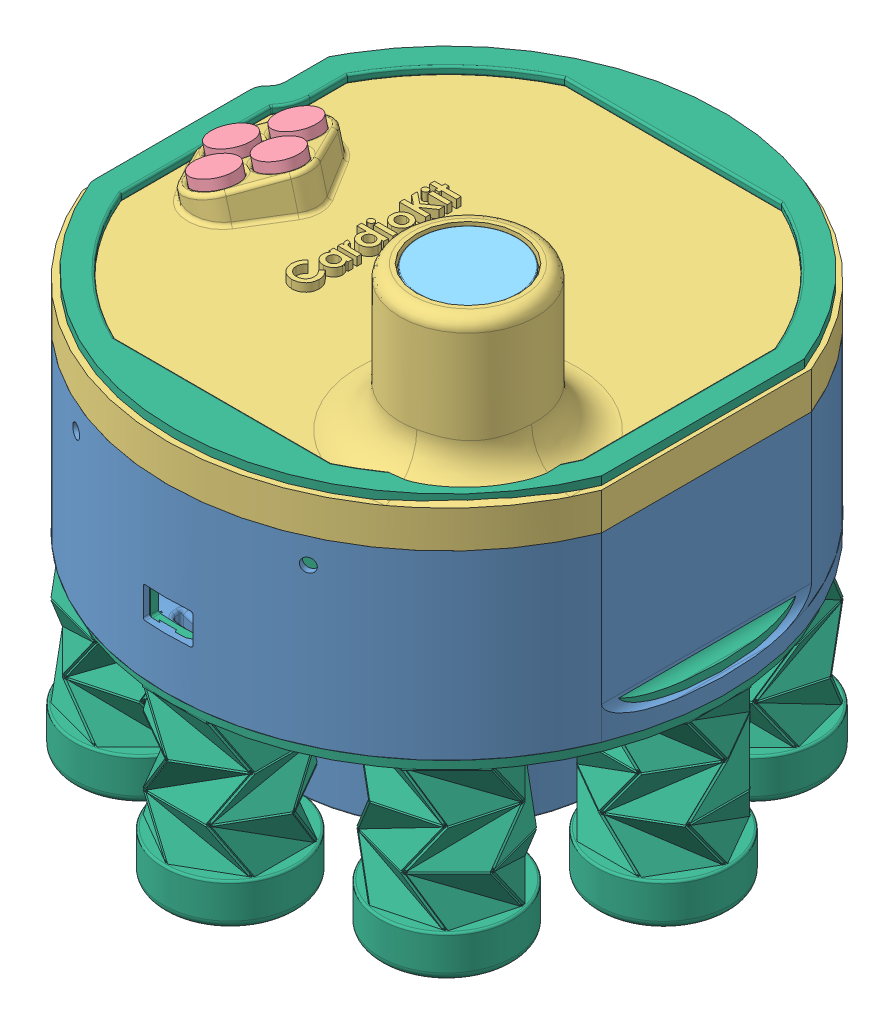
SolidWorks assembly CardioKit-Full-Assembly-R20, configuration Default. Lengths in mm.
Overall size (68.7 67.73 68.7).
46 component instances, 13 part files, 29 mates.
Components (placement in the parent):
- CardioKit_Shell_R00-1: CardioKit_Shell_R00 [Default] at (3.2379 48.1061 53.8338) size (67.95 39.64 67.99)
- CardioKitPCB_R01-1: CardioKitPCB_R01 [Default] at (3.2379 59.6836 53.8338) x (1 0 0) z (0 1 0) size (60.71 65.8 14.79)
- CardioKit_Shell_Top_R30-1: CardioKit_Shell_Top_R30 [Default] at (3.2379 72.6061 53.8338) x (1 0 0.000154) z (-0.000154 0 1) size (63 33.5 67.95)
- LED_5mm-1: LED_5mm [Default] at (-17.6564 71.4439 59.4672) x (-0.010288 -0.002809 -0.999943) z (0.965871 0.258804 -0.010664) size (5 11.8 5)
- LED_5mm-2: LED_5mm [Default] at (-14.7811 72.2141 54.4677) x (0.000332 0.000037 -1) z (0.965926 0.258819 0.00033) size (5 11.8 5)
- LED_5mm-3: LED_5mm [Default] at (-20.5766 70.6612 54.4666) x (0.005602 0.001449 -0.999983) z (0.96591 0.258815 0.005786) size (5 11.8 5)
- LED_5mm-4: LED_5mm [Default] at (-17.6544 71.4439 49.4672) x (0.014169 0.003744 -0.999893) z (0.965822 0.258792 0.014655) size (5 11.8 5)
- Sintered12mmElectrode-1: Sintered12mmElectrode [Default] at (20.3171 91.8561 68.3635) x (-0.837169 0 -0.546944) z (-0.546944 0 0.837169) size (12 5.38 12)
- Sintered12mmElectrode-2: Sintered12mmElectrode [Default] at (-29.0123 60.1061 53.8338) x (0 -0.932668 0.360735) z (0 0.360735 0.932668) size (12 5.38 12)
- CardioKit_Sock_R30-1: CardioKit_Sock_R30 [Default] at (3.2553 48.1061 53.8013) x (1 0 0.000196) z (-0.000196 0 1) size (68.69 51.15 68.69)
- ElectrodeAssembly-1: ElectrodeAssembly [Default] at (-23.7364 22.823 43.8978) size (11 27.01 11)
  - SpikedElectrodes-1: SpikedElectrodes [Default] at (0.6918 2.1948 9.9135) size (10.25 6.45 10.25)
  - ElectrodeHolder-1: ElectrodeHolder [Default] at (0.6918 4.8948 9.9135) x (0.999995 0 -0.003075) z (0.003075 0 0.999995) size (10 0.6 10)
  - Spring_R20_1pt7mmFinal2_Narrower-2: Spring_R20_1pt7mmFinal2_Narrower [Default] at (0.6918 3.1948 9.9135) x (1 0 0) z (0 -1 0) size (11 11 1.7)
- ElectrodeAssembly-2: ElectrodeAssembly [Default] at (-8.81 22.823 27.7342) x (0.707107 0 0.707107) z (-0.707107 0 0.707107) size (11 27.01 11)
  - SpikedElectrodes-1: SpikedElectrodes [Default] at (0.6918 2.1948 9.9135) size (10.25 6.45 10.25)
  - ElectrodeHolder-1: ElectrodeHolder [Default] at (0.6918 4.8948 9.9135) x (0.999995 0 -0.003075) z (0.003075 0 0.999995) size (10 0.6 10)
  - Spring_R20_1pt7mmFinal2_Narrower-2: Spring_R20_1pt7mmFinal2_Narrower [Default] at (0.6918 3.1948 9.9135) x (1 0 0) z (0 -1 0) size (11 11 1.7)
- ElectrodeAssembly-3: ElectrodeAssembly [Default] at (13.1739 22.823 26.8595) x (0 0 1) z (-1 0 0) size (11 27.01 11)
  - SpikedElectrodes-1: SpikedElectrodes [Default] at (0.6918 2.1948 9.9135) size (10.25 6.45 10.25)
  - ElectrodeHolder-1: ElectrodeHolder [Default] at (0.6918 4.8948 9.9135) x (0.999995 0 -0.003075) z (0.003075 0 0.999995) size (10 0.6 10)
  - Spring_R20_1pt7mmFinal2_Narrower-2: Spring_R20_1pt7mmFinal2_Narrower [Default] at (0.6918 3.1948 9.9135) x (1 0 0) z (0 -1 0) size (11 11 1.7)
- ElectrodeAssembly-4: ElectrodeAssembly [Default] at (29.3375 22.823 41.786) x (-0.707107 0 0.707107) z (-0.707107 0 -0.707107) size (11 27.01 11)
  - SpikedElectrodes-1: SpikedElectrodes [Default] at (0.6918 2.1948 9.9135) size (10.25 6.45 10.25)
  - ElectrodeHolder-1: ElectrodeHolder [Default] at (0.6918 4.8948 9.9135) x (0.999995 0 -0.003075) z (0.003075 0 0.999995) size (10 0.6 10)
  - Spring_R20_1pt7mmFinal2_Narrower-2: Spring_R20_1pt7mmFinal2_Narrower [Default] at (0.6918 3.1948 9.9135) x (1 0 0) z (0 -1 0) size (11 11 1.7)
- ElectrodeAssembly-5: ElectrodeAssembly [Default] at (30.2122 22.823 63.7699) x (-1 0 0) z (0 0 -1) size (11 27.01 11)
  - SpikedElectrodes-1: SpikedElectrodes [Default] at (0.6918 2.1948 9.9135) size (10.25 6.45 10.25)
  - ElectrodeHolder-1: ElectrodeHolder [Default] at (0.6918 4.8948 9.9135) x (0.999995 0 -0.003075) z (0.003075 0 0.999995) size (10 0.6 10)
  - Spring_R20_1pt7mmFinal2_Narrower-2: Spring_R20_1pt7mmFinal2_Narrower [Default] at (0.6918 3.1948 9.9135) x (1 0 0) z (0 -1 0) size (11 11 1.7)
- ElectrodeAssembly-6: ElectrodeAssembly [Default] at (15.2857 22.823 79.9334) x (-0.707107 0 -0.707107) z (0.707107 0 -0.707107) size (11 27.01 11)
  - SpikedElectrodes-1: SpikedElectrodes [Default] at (0.6918 2.1948 9.9135) size (10.25 6.45 10.25)
  - ElectrodeHolder-1: ElectrodeHolder [Default] at (0.6918 4.8948 9.9135) x (0.999995 0 -0.003075) z (0.003075 0 0.999995) size (10 0.6 10)
  - Spring_R20_1pt7mmFinal2_Narrower-2: Spring_R20_1pt7mmFinal2_Narrower [Default] at (0.6918 3.1948 9.9135) x (1 0 0) z (0 -1 0) size (11 11 1.7)
- ElectrodeAssembly-7: ElectrodeAssembly [Default] at (-6.6982 22.823 80.8082) x (0 0 -1) z (1 0 0) size (11 27.01 11)
  - SpikedElectrodes-1: SpikedElectrodes [Default] at (0.6918 2.1948 9.9135) size (10.25 6.45 10.25)
  - ElectrodeHolder-1: ElectrodeHolder [Default] at (0.6918 4.8948 9.9135) x (0.999995 0 -0.003075) z (0.003075 0 0.999995) size (10 0.6 10)
  - Spring_R20_1pt7mmFinal2_Narrower-2: Spring_R20_1pt7mmFinal2_Narrower [Default] at (0.6918 3.1948 9.9135) x (1 0 0) z (0 -1 0) size (11 11 1.7)
- ElectrodeAssembly-8: ElectrodeAssembly [Default] at (-22.8617 22.823 65.8817) x (0.707107 0 -0.707107) z (0.707107 0 0.707107) size (11 27.01 11)
  - SpikedElectrodes-1: SpikedElectrodes [Default] at (0.6918 2.1948 9.9135) size (10.25 6.45 10.25)
  - ElectrodeHolder-1: ElectrodeHolder [Default] at (0.6918 4.8948 9.9135) x (0.999995 0 -0.003075) z (0.003075 0 0.999995) size (10 0.6 10)
  - Spring_R20_1pt7mmFinal2_Narrower-2: Spring_R20_1pt7mmFinal2_Narrower [Default] at (0.6918 3.1948 9.9135) x (1 0 0) z (0 -1 0) size (11 11 1.7)
- MeasurementSpecialties_CM_01B-1: MeasurementSpecialties_CM_01B [Default] at (3.2379 41.4661 53.8338) x (-0.837169 0 -0.546944) z (-0.546944 0 0.837169) size (20.2 11 18.2)
- 310-105_PrecisionMicrodrives-1: 310-105_PrecisionMicrodrives [Default] at (-10.7321 53.9561 77.013) size (12 4.01 10)
- Micro SD Card-1: Micro SD Card [Default] at (-34.8284 58.0561 10.8246) x (1 0 0) z (0 -1 0) size (11.02 15.01 1.01)
- Tenergy_1000mAh_RectangularLiPo-1: Tenergy_1000mAh_RectangularLiPo [Default] at (5.4879 68.2061 53.8028) x (1 0 0.000154) z (-0.000154 0 1) size (34.5 5.4 54.5)
Mates (geometry in assembly coordinates):
- Concentric1: concentric anti-aligned: cylinder of CardioKit_Shell_R00-1 through (3.2379 88.556 53.8338) axis (0 -1 0) radius 10.2; cylinder of CardioKitPCB_R01-1 through (3.2379 58.105 53.8338) axis (0 1 0) radius 10.5
- Coincident1: coincident anti-aligned: plane of CardioKit_Shell_R00-1 through (3.2379 58.1061 53.8338) normal (0 1 0); plane of CardioKitPCB_R01-1 through (-26.7659 58.1061 66.262) normal (0 -1 0)
- Parallel1: parallel aligned: plane of CardioKit_Shell_R00-1 through (34.7417 50.1061 41.1113) normal (1 0 0.000154); plane of CardioKitPCB_R01-1 through (33.2379 58.1061 66.2713) normal (1 0 0.000154)
- Coincident3: coincident aligned: line of CardioKit_Shell_R00-1 through (-28.2621 70.1061 46.5173) axis (-0.000196 0 1); line of CardioKit_Shell_Top_R30-1 through (-28.2621 70.1061 46.5173) axis (-0.000196 0 1)
- Coincident4: coincident anti-aligned: line of CardioKit_Shell_R00-1 through (34.7378 70.1061 66.5665) axis (0 -1 0); line of CardioKit_Shell_Top_R30-1 through (34.7378 70.1061 66.5665) axis (0 1 0)
- Coincident6: coincident aligned: circle of CardioKit_Shell_Top_R30-1; circle of LED_5mm-1
- Coincident7: coincident aligned: circle of CardioKit_Shell_Top_R30-1; circle of LED_5mm-3
- Coincident8: coincident aligned: circle of CardioKit_Shell_Top_R30-1; circle of LED_5mm-2
- Coincident9: coincident aligned: circle of CardioKit_Shell_Top_R30-1; circle of LED_5mm-4
- Concentric3: concentric anti-aligned: cylinder of CardioKit_Shell_R00-1 through (3.2379 60.1061 53.8338) axis (1 0 0) radius 6.25; cylinder of Sintered12mmElectrode-2 through (-28.0123 60.1061 53.8338) axis (-1 0 0) radius 6
- Coincident16: coincident anti-aligned: circle of CardioKit_Shell_R00-1; plane of Sintered12mmElectrode-2 through (-29.0123 60.1061 53.8338) normal (-1 0 0)
- Coincident17: coincident anti-aligned: plane of CardioKit_Shell_Top_R30-1 through (3.2379 90.8561 53.8338) normal (0 1 0); plane of Sintered12mmElectrode-1 through (20.3171 90.8561 68.3635) normal (0 -1 0)
- Concentric4: concentric anti-aligned: cylinder of CardioKit_Shell_Top_R30-1 through (20.3171 92.1061 68.3635) axis (0 -1 0) radius 6.25; cylinder of Sintered12mmElectrode-1 through (20.3171 90.8561 68.3635) axis (0 1 0) radius 6
- Coincident19: coincident anti-aligned: plane of CardioKit_Shell_R00-1 through (-26.7659 48.1061 66.262) normal (0 -1 0); plane of CardioKit_Sock_R30-1 through (-25.2658 48.1061 65.6406) normal (0 1 0)
- Parallel6: parallel aligned: plane of CardioKit_Shell_R00-1 through (34.7417 50.1061 41.1113) normal (1 0 0.000154); plane of CardioKit_Sock_R30-1 through (34.2372 75.6061 53.8061) normal (1 0 0.000154)
- Concentric5: concentric aligned: cylinder of CardioKit_Shell_R00-1 through (3.2379 48.1061 53.8338) axis (0 -1 0) radius 19; cylinder of CardioKit_Sock_R30-1 through (3.2379 48.1061 53.8338) axis (0 -1 0) radius 17.1
- Coincident21: coincident aligned: plane of CardioKit_Sock_R30-1 through (-28.1447 25.0178 53.8103) normal (0 -1 0); plane of ElectrodeAssembly-1/SpikedElectrodes-1 through (-23.0447 25.0178 53.8113) normal (0 -1 0)
- Concentric6: concentric anti-aligned: circle of CardioKit_Sock_R30-1; circle of ElectrodeAssembly-1/SpikedElectrodes-1
- Concentric7: concentric anti-aligned: cylinder of CardioKit_Shell_R00-1 through (3.2379 48.1061 53.8338) axis (0 -1 0) radius 9.35; cylinder of MeasurementSpecialties_CM_01B-1 through (3.2379 33.4661 53.8338) axis (0 1 0) radius 9.1
- Coincident22: coincident aligned: plane of CardioKit_Shell_R00-1 through (3.2379 30.4661 35.1338) normal (0 -1 0); plane of MeasurementSpecialties_CM_01B-1 through (3.2379 30.4661 53.8338) normal (0 -1 0)
- Coincident23: coincident anti-aligned: plane of CardioKit_Shell_R00-1 through (3.2379 53.9561 53.8338) normal (0 1 0); plane of 310-105_PrecisionMicrodrives-1 through (-10.7321 53.9561 77.013) normal (0 -1 0)
- Perpendicular2: perpendicular: line of CardioKit_Shell_R00-1 through (-5.8991 53.9561 75.163) axis (1 0 0); line of 310-105_PrecisionMicrodrives-1 through (-3.7321 53.9561 78.613) axis (0 0 -1)
- Concentric8: concentric aligned: cylinder of CardioKit_Shell_R00-1 through (-10.7321 71.2348 77.013) axis (0 -1 0) radius 5.175; cylinder of 310-105_PrecisionMicrodrives-1 through (-10.7321 57.4061 77.013) axis (0 -1 0) radius 5
- Coincident25: coincident anti-aligned: plane of CardioKit_Shell_R00-1 through (-5.0745 58.0561 87.8109) normal (0 -1 0); plane of Micro SD Card-1 through (-16.4406 58.0561 19.8581) normal (0 1 0)
- Tangent3: tangent: circle of CardioKit_Shell_R00-1; plane of Micro SD Card-1 through (-6.3015 58.0561 19.8581) normal (0 0 -1)
- Coincident29: coincident: line of CardioKit_Shell_R00-1 through (-16.3745 56.869 26.0893) axis (0 1 0); plane of Micro SD Card-1 through (-16.3745 58.0561 21.3462) normal (-1 0 0)
- Coincident30: coincident anti-aligned: plane of CardioKit_Shell_Top_R30-1 through (3.2379 73.6061 53.834) normal (0 -1 0); plane of Tenergy_1000mAh_RectangularLiPo-1 through (5.4879 73.6061 53.8028) normal (0 1 0)
- Coincident31: coincident: line of CardioKit_Shell_Top_R30-1 through (-11.762 72.5053 52.6998) axis (-0.000154 0.000011 1); plane of Tenergy_1000mAh_RectangularLiPo-1 through (-11.766 73.6061 79.0501) normal (-1 0 -0.000154)
- Tangent4: tangent aligned: cylinder of CardioKit_Shell_Top_R30-1 through (3.2379 40.367 53.834) axis (0 1 0) radius 31.4759; cylinder of Tenergy_1000mAh_RectangularLiPo-1 through (21.7342 73.6061 78.0553) axis (0 -1 0) radius 1
